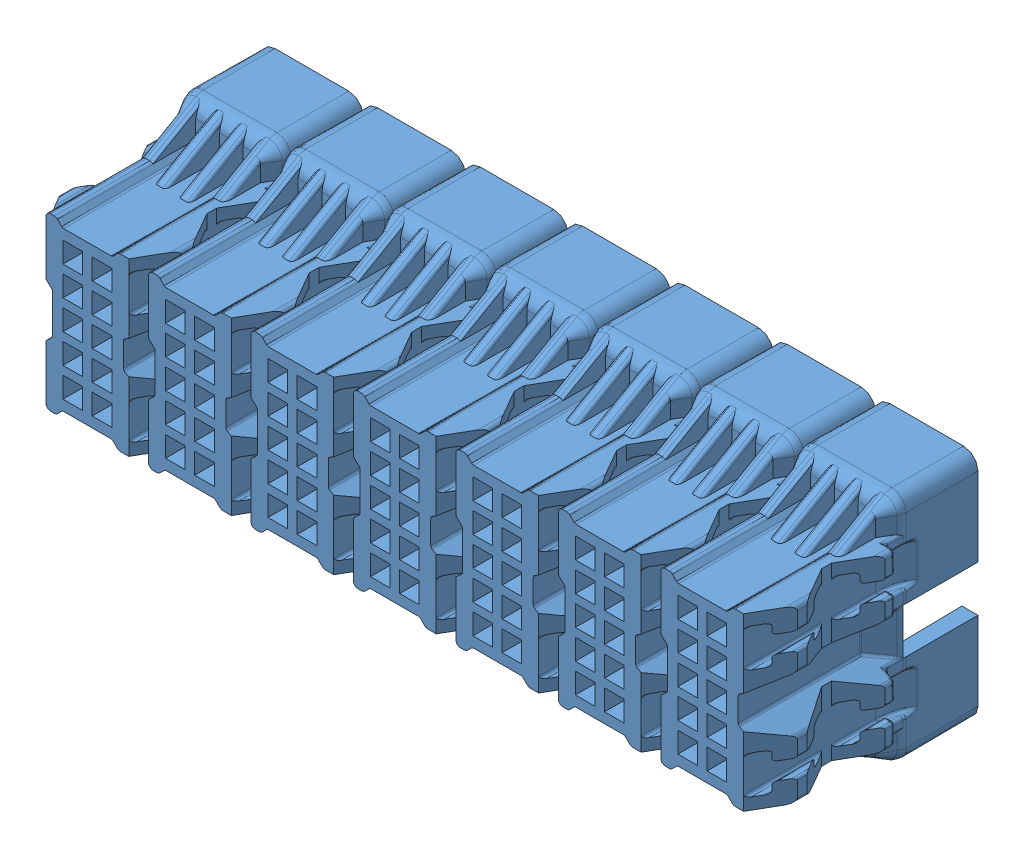
SolidWorks assembly Flatwire connectors, configuration Default. Lengths in mm.
Overall size (64.01 20.2 19.5).
7 component instances, 1 part files, 21 mates.
Components (placement in the parent):
- 10 pin socket transfer port mainboard V2-1: 10 pin socket transfer port mainboard V2 [Default] at (-26.7 0 0) x (0 -1 0) z (-1 0 0) size (20.2 19.5 10.61)
- 10 pin socket transfer port mainboard V2-2: 10 pin socket transfer port mainboard V2 [Default] at (-17.8 0 0) x (0 -1 0) z (-1 0 0) size (20.2 19.5 10.61)
- 10 pin socket transfer port mainboard V2-3: 10 pin socket transfer port mainboard V2 [Default] at (-8.9 0 0) x (0 -1 0) z (-1 0 0) size (20.2 19.5 10.61)
- 10 pin socket transfer port mainboard V2-4: 10 pin socket transfer port mainboard V2 [Default] x (0 -1 0) z (-1 0 0) size (20.2 19.5 10.61)
- 10 pin socket transfer port mainboard V2-5: 10 pin socket transfer port mainboard V2 [Default] at (8.9 0 0) x (0 -1 0) z (-1 0 0) size (20.2 19.5 10.61)
- 10 pin socket transfer port mainboard V2-6: 10 pin socket transfer port mainboard V2 [Default] at (17.8 0 0) x (0 -1 0) z (-1 0 0) size (20.2 19.5 10.61)
- 10 pin socket transfer port mainboard V2-7: 10 pin socket transfer port mainboard V2 [Default] at (26.7 0 0) x (0 -1 0) z (-1 0 0) size (20.2 19.5 10.61)
Mates (geometry in assembly coordinates):
- Coincident38: coincident aligned: plane of 10 pin socket transfer port mainboard V2-1 through (-22.25 -10.1 6.5) normal (0 -1 0); plane of 10 pin socket transfer port mainboard V2-2 through (-13.35 -10.1 6.5) normal (0 -1 0)
- Coincident43: coincident aligned: plane of 10 pin socket transfer port mainboard V2-1 through (-26.7 0 0) normal (0 0 -1); plane of 10 pin socket transfer port mainboard V2-2 through (-17.8 0 0) normal (0 0 -1)
- Coincident48: coincident anti-aligned: plane of 10 pin socket transfer port mainboard V2-1 through (-22.25 10.1 6.5) normal (1 0 0); plane of 10 pin socket transfer port mainboard V2-2 through (-22.25 10.1 6.5) normal (-1 0 0)
- Coincident39: coincident aligned: plane of 10 pin socket transfer port mainboard V2-1 through (-22.25 -10.1 6.5) normal (0 -1 0); plane of 10 pin socket transfer port mainboard V2-3 through (-4.45 -10.1 6.5) normal (0 -1 0)
- Coincident44: coincident aligned: plane of 10 pin socket transfer port mainboard V2-1 through (-26.7 0 0) normal (0 0 -1); plane of 10 pin socket transfer port mainboard V2-3 through (-8.9 0 0) normal (0 0 -1)
- Coincident49: coincident anti-aligned: plane of 10 pin socket transfer port mainboard V2-2 through (-13.35 10.1 6.5) normal (1 0 0); plane of 10 pin socket transfer port mainboard V2-3 through (-13.35 10.1 6.5) normal (-1 0 0)
- Coincident40: coincident aligned: plane of 10 pin socket transfer port mainboard V2-1 through (-22.25 -10.1 6.5) normal (0 -1 0); plane of 10 pin socket transfer port mainboard V2-4 through (4.45 -10.1 6.5) normal (0 -1 0)
- Coincident45: coincident aligned: plane of 10 pin socket transfer port mainboard V2-1 through (-26.7 0 0) normal (0 0 -1); plane of 10 pin socket transfer port mainboard V2-4 through (0 0 0) normal (0 0 -1)
- Coincident50: coincident anti-aligned: plane of 10 pin socket transfer port mainboard V2-3 through (-4.45 10.1 6.5) normal (1 0 0); plane of 10 pin socket transfer port mainboard V2-4 through (-4.45 10.1 6.5) normal (-1 0 0)
- Coincident41: coincident aligned: plane of 10 pin socket transfer port mainboard V2-1 through (-22.25 -10.1 6.5) normal (0 -1 0); plane of 10 pin socket transfer port mainboard V2-5 through (13.35 -10.1 6.5) normal (0 -1 0)
- Coincident46: coincident aligned: plane of 10 pin socket transfer port mainboard V2-1 through (-26.7 0 0) normal (0 0 -1); plane of 10 pin socket transfer port mainboard V2-5 through (8.9 0 0) normal (0 0 -1)
- Coincident51: coincident anti-aligned: plane of 10 pin socket transfer port mainboard V2-4 through (4.45 10.1 6.5) normal (1 0 0); plane of 10 pin socket transfer port mainboard V2-5 through (4.45 10.1 6.5) normal (-1 0 0)
- Coincident42: coincident aligned: plane of 10 pin socket transfer port mainboard V2-1 through (-22.25 -10.1 6.5) normal (0 -1 0); plane of 10 pin socket transfer port mainboard V2-6 through (22.25 -10.1 6.5) normal (0 -1 0)
- Coincident47: coincident aligned: plane of 10 pin socket transfer port mainboard V2-1 through (-26.7 0 0) normal (0 0 -1); plane of 10 pin socket transfer port mainboard V2-6 through (17.8 0 0) normal (0 0 -1)
- Coincident53: coincident anti-aligned: plane of 10 pin socket transfer port mainboard V2-5 through (13.35 10.1 6.5) normal (1 0 0); plane of 10 pin socket transfer port mainboard V2-6 through (13.35 10.1 6.5) normal (-1 0 0)
- Coincident54: coincident anti-aligned: plane of 10 pin socket transfer port mainboard V2-6 through (22.25 10.1 6.5) normal (1 0 0); plane of 10 pin socket transfer port mainboard V2-7 through (22.25 10.1 6.5) normal (-1 0 0)
- Coincident55: coincident aligned: plane of 10 pin socket transfer port mainboard V2-6 through (22.25 10.1 6.5) normal (0 1 0); plane of 10 pin socket transfer port mainboard V2-7 through (31.15 10.1 6.5) normal (0 1 0)
- Coincident56: coincident aligned: plane of 10 pin socket transfer port mainboard V2-6 through (17.8 0 0) normal (0 0 -1); plane of 10 pin socket transfer port mainboard V2-7 through (26.7 0 0) normal (0 0 -1)
- Coincident57: coincident anti-aligned: plane of 10 pin socket transfer port mainboard V2-4 through (0 0 0) normal (-1 0 0); plane of assembly through (0 0 0) normal (1 0 0)
- Coincident58: coincident anti-aligned: plane of 10 pin socket transfer port mainboard V2-1; plane of assembly through (0 0 0) normal (0 1 0)
- Coincident59: coincident aligned: plane of 10 pin socket transfer port mainboard V2-1; plane of assembly through (0 0 0) normal (0 0 1)
